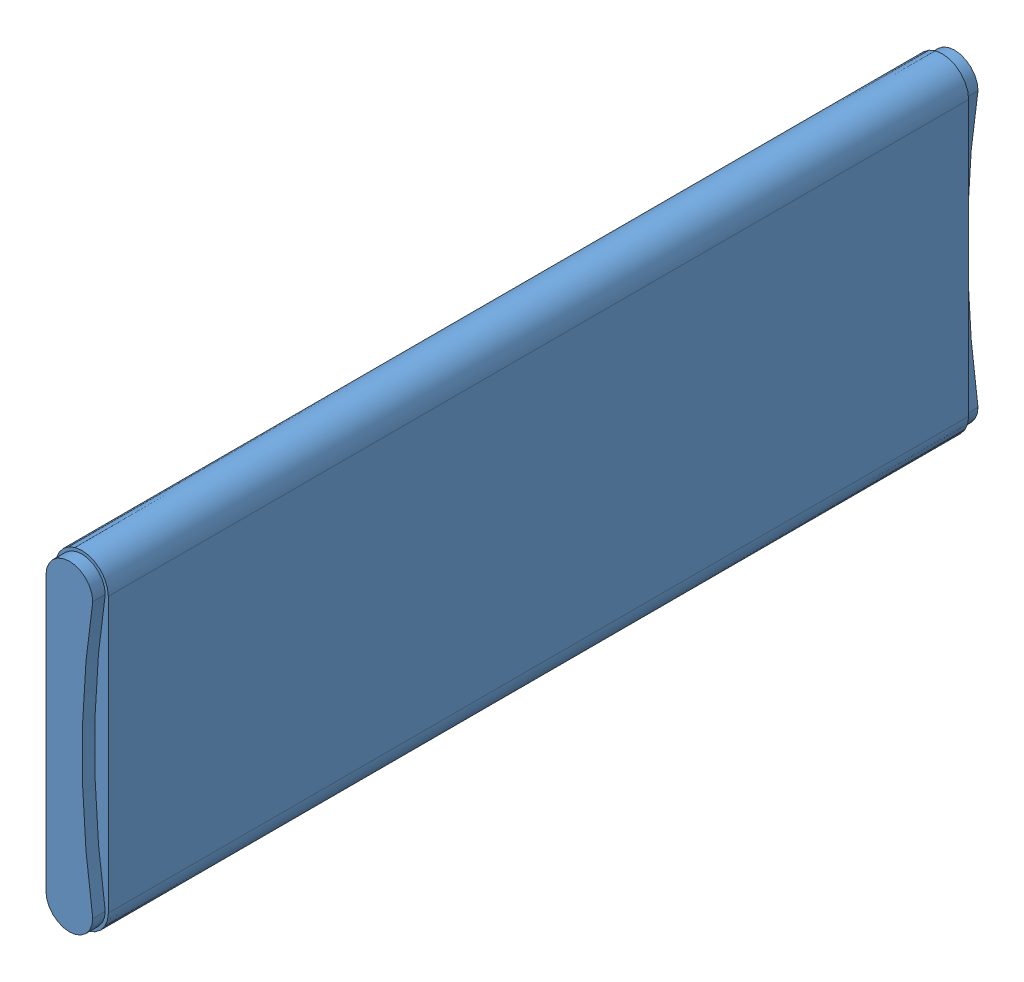
SolidWorks assembly Keyboard, configuration Default. Lengths in mm.
Overall size (33.34 166.69 450.85).
53 component instances, 12 part files, 45 mates.
Components (placement in the parent):
- keyboard-1: keyboard [Default] at (129.1547 266.0626 122.0532) size (33.34 166.69 450.85)
- squre button-1: squre button [Default] at (115.6609 262.8876 162.1375) x (0 1 0) z (0 0 1) size (19.05 6.35 19.05)
- squre button-2: squre button [Default] at (115.6609 262.8876 181.5844) x (0 1 0) z (0 0 1) size (19.05 6.35 19.05)
- squre button-3: squre button [Default] at (115.6609 262.8876 201.0313) x (0 1 0) z (0 0 1) size (19.05 6.35 19.05)
- squre button-4: squre button [Default] at (115.6609 262.8876 220.4782) x (0 1 0) z (0 0 1) size (19.05 6.35 19.05)
- squre button-5: squre button [Default] at (115.6609 262.8876 239.925) x (0 1 0) z (0 0 1) size (19.05 6.35 19.05)
- squre button-6: squre button [Default] at (115.6609 262.8876 259.3719) x (0 1 0) z (0 0 1) size (19.05 6.35 19.05)
- squre button-7: squre button [Default] at (115.6609 262.8876 278.8188) x (0 1 0) z (0 0 1) size (19.05 6.35 19.05)
- squre button-8: squre button [Default] at (115.6609 262.8876 298.2657) x (0 1 0) z (0 0 1) size (19.05 6.35 19.05)
- squre button-9: squre button [Default] at (115.6609 262.8876 317.7125) x (0 1 0) z (0 0 1) size (19.05 6.35 19.05)
- squre button-10: squre button [Default] at (115.6609 262.8876 337.1594) x (0 1 0) z (0 0 1) size (19.05 6.35 19.05)
- squre button-11: squre button [Default] at (115.6609 262.8876 356.6063) x (0 1 0) z (0 0 1) size (19.05 6.35 19.05)
- squre button-12: squre button [Default] at (115.6609 262.8876 376.0532) x (0 1 0) z (0 0 1) size (19.05 6.35 19.05)
- squre button-13: squre button [Default] at (115.6609 243.4407 168.4875) x (0 1 0) z (0 0 1) size (19.05 6.35 19.05)
- squre button-14: squre button [Default] at (115.6609 243.4407 187.9344) x (0 1 0) z (0 0 1) size (19.05 6.35 19.05)
- squre button-15: squre button [Default] at (115.6609 243.4407 207.3813) x (0 1 0) z (0 0 1) size (19.05 6.35 19.05)
- squre button-16: squre button [Default] at (115.6609 243.4407 226.8282) x (0 1 0) z (0 0 1) size (19.05 6.35 19.05)
- squre button-17: squre button [Default] at (115.6609 243.4407 246.275) x (0 1 0) z (0 0 1) size (19.05 6.35 19.05)
- squre button-18: squre button [Default] at (115.6609 243.4407 265.7219) x (0 1 0) z (0 0 1) size (19.05 6.35 19.05)
- squre button-19: squre button [Default] at (115.6609 243.4407 285.1688) x (0 1 0) z (0 0 1) size (19.05 6.35 19.05)
- squre button-20: squre button [Default] at (115.6609 243.4407 304.6157) x (0 1 0) z (0 0 1) size (19.05 6.35 19.05)
- squre button-21: squre button [Default] at (115.6609 243.4407 324.0625) x (0 1 0) z (0 0 1) size (19.05 6.35 19.05)
- squre button-22: squre button [Default] at (115.6609 243.4407 343.5094) x (0 1 0) z (0 0 1) size (19.05 6.35 19.05)
- squre button-23: squre button [Default] at (115.6609 243.4407 362.9563) x (0 1 0) z (0 0 1) size (19.05 6.35 19.05)
- squre button-24: squre button [Default] at (115.6609 243.4407 382.4032) x (0 1 0) z (0 0 1) size (19.05 6.35 19.05)
- squre button-25: squre button [Default] at (115.6609 223.9939 178.0125) x (0 1 0) z (0 0 1) size (19.05 6.35 19.05)
- squre button-26: squre button [Default] at (115.6609 223.9939 197.4594) x (0 1 0) z (0 0 1) size (19.05 6.35 19.05)
- squre button-27: squre button [Default] at (115.6609 223.9939 216.9063) x (0 1 0) z (0 0 1) size (19.05 6.35 19.05)
- squre button-28: squre button [Default] at (115.6609 223.9939 236.3532) x (0 1 0) z (0 0 1) size (19.05 6.35 19.05)
- squre button-29: squre button [Default] at (115.6609 223.9939 255.8) x (0 1 0) z (0 0 1) size (19.05 6.35 19.05)
- squre button-30: squre button [Default] at (115.6609 223.9939 275.2469) x (0 1 0) z (0 0 1) size (19.05 6.35 19.05)
- squre button-31: squre button [Default] at (115.6609 223.9939 294.6938) x (0 1 0) z (0 0 1) size (19.05 6.35 19.05)
- squre button-32: squre button [Default] at (115.6609 223.9939 314.1407) x (0 1 0) z (0 0 1) size (19.05 6.35 19.05)
- squre button-33: squre button [Default] at (115.6609 223.9939 333.5875) x (0 1 0) z (0 0 1) size (19.05 6.35 19.05)
- squre button-34: squre button [Default] at (115.6609 223.9939 353.0344) x (0 1 0) z (0 0 1) size (19.05 6.35 19.05)
- 0-1: 0 [Default] at (115.6609 204.547 521.7063) x (0 0 -1) z (0 1 0) size (38.5 6.35 19.05)
- + nand Enter-1: + nand Enter [Default] at (115.6609 243.4407 541.55) x (0 1 0) z (0 0 1) size (38.5 6.35 19.05)
- + nand Enter-2: + nand Enter [Default] at (115.6609 204.547 541.55) x (0 1 0) z (0 0 1) size (38.5 6.35 19.05)
- Enter-1: Enter [Default] at (115.6609 281.9376 395.5) x (0 0 1) z (0 -1 0) size (22.62 6.35 38.5)
- backspace-1: backspace [Default] at (115.6609 301.3845 385.975) x (0 0 1) z (0 -1 0) size (32.23 6.35 19.05)
- Shift 2-1: Shift 2 [Default] at (115.6609 243.0439 133.1657) x (0 0 1) z (0 -1 0) size (45.64 6.35 19.05)
- Shift 2-2: Shift 2 [Default] at (115.6609 243.0439 372.4813) x (0 0 1) z (0 -1 0) size (45.64 6.35 19.05)
- Shift - Copy-1: Shift - Copy [Default] at (115.6609 281.9376 133.1657) x (0 0 1) z (0 -1 0) size (28.57 6.35 19.05)
- caps ;ock-1: caps ;ock [Default] at (115.6609 262.4907 133.1657) x (0 0 1) z (0 -1 0) size (35.01 6.35 19.05)
- Ctrl-1: Ctrl [Default] at (115.6609 223.597 133.1657) x (0 0 1) z (0 -1 0) size (23.81 6.35 19.05)
- Ctrl-2: Ctrl [Default] at (115.6609 223.597 157.375) x (0 0 1) z (0 -1 0) size (23.81 6.35 19.05)
- Ctrl-3: Ctrl [Default] at (115.6609 223.597 181.5844) x (0 0 1) z (0 -1 0) size (23.81 6.35 19.05)
- Ctrl-11: Ctrl [Default] at (115.6609 204.547 418.1219) x (0 0 -1) z (0 1 0) size (23.81 6.35 19.05)
- Ctrl-12: Ctrl [Default] at (115.6609 204.547 393.9125) x (0 0 -1) z (0 1 0) size (23.81 6.35 19.05)
- Ctrl-13: Ctrl [Default] at (115.6609 204.547 369.7032) x (0 0 -1) z (0 1 0) size (23.81 6.35 19.05)
- Ctrl-14: Ctrl [Default] at (115.6609 204.547 345.4938) x (0 0 -1) z (0 1 0) size (23.81 6.35 19.05)
- Space-1: Space [Default] at (115.6609 223.597 205.7938) x (0 0 1) z (0 -1 0) size (115.49 6.35 19.05)
- Part2^Keyboard-1: Part2^Keyboard [Default] at origin (virtual)
Mates (geometry in assembly coordinates):
- Coincident1: coincident anti-aligned: plane of keyboard-1 through (115.6609 196.2126 572.9032) normal (-1 0 0); plane of squre button-1 through (115.6609 262.8876 162.1375) normal (1 0 0)
- Distance1: distance = 0.3969 mm: line of squre button-1 through (115.6609 281.9376 162.1375) axis (0 0 1); line of keyboard-1 through (115.6609 282.3345 152.6125) axis (0 0 1)
- Distance3: distance = 9.525 mm: line of squre button-1 through (115.6609 262.8876 162.1375) axis (0 1 0); line of keyboard-1 through (115.6609 282.3345 171.6625) axis (0 1 0)
- Coincident5: coincident anti-aligned: plane of keyboard-1 through (115.6609 196.2126 572.9032) normal (-1 0 0); plane of squre button-13 through (115.6609 243.4407 168.4875) normal (1 0 0)
- Distance4: distance = 0.3969 mm: line of squre button-13 through (115.6609 262.4907 168.4875) axis (0 0 1); line of squre button-1 through (115.6609 262.8876 162.1375) axis (0 0 1)
- Distance5: distance = 12.7 mm: line of squre button-13 through (115.6609 243.4407 168.4875) axis (0 1 0); line of squre button-1 through (115.6609 262.8876 181.1875) axis (0 1 0)
- Coincident8: coincident anti-aligned: plane of keyboard-1 through (115.6609 196.2126 572.9032) normal (-1 0 0); plane of squre button-25 through (115.6609 223.9939 178.0125) normal (1 0 0)
- Distance6: distance = 0.3969 mm: line of squre button-25 through (115.6609 243.0439 178.0125) axis (0 0 1); line of squre button-13 through (115.6609 243.4407 168.4875) axis (0 0 1)
- Distance7: distance = 9.525 mm: line of squre button-25 through (115.6609 223.9939 178.0125) axis (0 1 0); line of squre button-13 through (115.6609 243.4407 187.5375) axis (0 1 0)
- Coincident11: coincident anti-aligned: plane of keyboard-1 through (115.6609 196.2126 572.9032) normal (-1 0 0); plane of 0-1 through (115.6609 204.547 521.7063) normal (1 0 0)
- Distance12: distance = 0.3969 mm: line of 0-1 through (115.6609 204.547 521.7063) axis (0 0 -1); line of keyboard-1 through (115.6609 204.1501 483.2094) axis (0 0 1)
- Coincident16: coincident anti-aligned: line of keyboard-1 through (115.6609 243.0439 483.2094) axis (0 -1 0); line of 0-1 through (115.6609 204.547 483.2094) axis (0 1 0)
- Coincident17: coincident anti-aligned: plane of keyboard-1 through (115.6609 196.2126 572.9032) normal (-1 0 0); plane of + nand Enter-1 through (115.6609 243.4407 541.55) normal (1 0 0)
- Distance13: distance = 0.3969 mm: line of + nand Enter-1 through (115.6609 281.9376 560.6) axis (0 0 -1); line of keyboard-1 through (115.6609 282.3345 541.55) axis (0 0 1)
- Coincident19: coincident aligned: line of keyboard-1 through (115.6609 301.3845 541.55) axis (0 -1 0); line of + nand Enter-1 through (115.6609 281.9376 541.55) axis (0 -1 0)
- Coincident20: coincident anti-aligned: plane of keyboard-1 through (115.6609 196.2126 572.9032) normal (-1 0 0); plane of + nand Enter-2 through (115.6609 204.547 541.55) normal (1 0 0)
- Distance14: distance = 0.3969 mm: line of + nand Enter-2 through (115.6609 243.0439 560.6) axis (0 0 -1); line of + nand Enter-1 through (115.6609 243.4407 541.55) axis (0 0 1)
- Coincident22: coincident aligned: line of + nand Enter-1 through (115.6609 281.9376 541.55) axis (0 -1 0); line of + nand Enter-2 through (115.6609 243.0439 541.55) axis (0 -1 0)
- Coincident24: coincident anti-aligned: plane of keyboard-1 through (115.6609 196.2126 572.9032) normal (-1 0 0); plane of Enter-1 through (115.6609 281.9376 395.5) normal (1 0 0)
- Coincident37: coincident aligned: line of squre button-12 through (115.6609 281.9376 376.0532) axis (0 0 1); line of Enter-1 through (115.6609 281.9376 395.5) axis (0 0 1)
- Distance24: distance = 0.3969 mm: line of Enter-1 through (115.6609 262.8876 395.5) axis (0 1 0); line of squre button-12 through (115.6609 262.8876 395.1032) axis (0 1 0)
- Coincident39: coincident anti-aligned: plane of keyboard-1 through (115.6609 196.2126 572.9032) normal (-1 0 0); plane of backspace-1 through (115.6609 301.3845 385.975) normal (1 0 0)
- Distance27: distance = 0.3969 mm: line of backspace-1 through (115.6609 301.3845 385.975) axis (0 -1 0); line of keyboard-1 through (115.6609 282.3345 385.5782) axis (0 1 0)
- Coincident44: coincident aligned: line of keyboard-1 through (115.6609 301.3845 385.5782) axis (0 0 -1); line of backspace-1 through (115.6609 301.3845 418.2013) axis (0 0 -1)
- Coincident45: coincident anti-aligned: plane of keyboard-1 through (115.6609 196.2126 572.9032) normal (-1 0 0); plane of Shift 2-1 through (115.6609 243.0439 133.1657) normal (1 0 0)
- Coincident47: coincident aligned: line of squre button-34 through (115.6609 243.0439 353.0344) axis (0 0 1); line of Shift 2-1 through (115.6609 243.0439 133.1657) axis (0 0 1)
- Distance32: distance = 0.3969 mm: line of Shift 2-1 through (115.6609 243.0439 133.1657) axis (0 -1 0); line of keyboard-1 through (115.6609 301.3845 132.7688) axis (0 -1 0)
- Coincident55: coincident anti-aligned: plane of keyboard-1 through (115.6609 196.2126 572.9032) normal (-1 0 0); plane of Shift 2-2 through (115.6609 243.0439 372.4813) normal (1 0 0)
- Coincident57: coincident aligned: line of squre button-34 through (115.6609 243.0439 353.0344) axis (0 0 1); line of Shift 2-2 through (115.6609 243.0439 372.4813) axis (0 0 1)
- Distance33: distance = 0.3969 mm: line of Shift 2-2 through (115.6609 243.0439 372.4813) axis (0 -1 0); line of squre button-34 through (115.6609 223.9939 372.0844) axis (0 1 0)
- Coincident59: coincident anti-aligned: plane of keyboard-1 through (115.6609 196.2126 572.9032) normal (-1 0 0); plane of Shift - Copy-1 through (115.6609 281.9376 133.1657) normal (1 0 0)
- Coincident62: coincident aligned: line of squre button-1 through (115.6609 281.9376 162.1375) axis (0 0 1); line of Shift - Copy-1 through (115.6609 281.9376 133.1657) axis (0 0 1)
- Distance34: distance = 0.3969 mm: line of Shift - Copy-1 through (115.6609 281.9376 133.1657) axis (0 -1 0); line of keyboard-1 through (115.6609 301.3845 132.7688) axis (0 -1 0)
- Coincident63: coincident anti-aligned: plane of keyboard-1 through (115.6609 196.2126 572.9032) normal (-1 0 0); plane of caps ;ock-1 through (115.6609 262.4907 133.1657) normal (1 0 0)
- Coincident64: coincident aligned: line of squre button-13 through (115.6609 262.4907 168.4875) axis (0 0 1); line of caps ;ock-1 through (115.6609 262.4907 133.1657) axis (0 0 1)
- Coincident65: coincident aligned: line of Shift - Copy-1 through (115.6609 281.9376 133.1657) axis (0 -1 0); line of caps ;ock-1 through (115.6609 262.4907 133.1657) axis (0 -1 0)
- Coincident66: coincident anti-aligned: plane of keyboard-1 through (115.6609 196.2126 572.9032) normal (-1 0 0); plane of Ctrl-1 through (115.6609 223.597 133.1657) normal (1 0 0)
- Coincident69: coincident aligned: line of Ctrl-1 through (115.6609 223.597 133.1657) axis (0 -1 0); line of Shift 2-1 through (115.6609 243.0439 133.1657) axis (0 -1 0)
- Distance37: distance = 0.3969 mm: line of Ctrl-1 through (115.6609 223.597 133.1657) axis (0 0 1); line of Shift 2-1 through (115.6609 223.9939 133.1657) axis (0 0 1)
- Coincident71: coincident anti-aligned: plane of keyboard-1 through (115.6609 196.2126 572.9032) normal (-1 0 0); plane of Ctrl-11 through (115.6609 204.547 418.1219) normal (1 0 0)
- Coincident73: coincident anti-aligned: line of Ctrl-3 through (115.6609 223.597 181.5844) axis (0 0 1); line of Ctrl-11 through (115.6609 223.597 418.1219) axis (0 0 -1)
- Coincident74: coincident anti-aligned: line of Shift 2-2 through (115.6609 243.0439 418.1219) axis (0 -1 0); line of Ctrl-11 through (115.6609 204.547 418.1219) axis (0 1 0)
- Coincident75: coincident anti-aligned: plane of keyboard-1 through (115.6609 196.2126 572.9032) normal (-1 0 0); plane of Space-1 through (115.6609 223.597 205.7938) normal (1 0 0)
- Coincident76: coincident aligned: line of Ctrl-3 through (115.6609 223.597 181.5844) axis (0 0 1); line of Space-1 through (115.6609 223.597 205.7938) axis (0 0 1)
- Distance38: distance = 0.3969 mm: line of Space-1 through (115.6609 223.597 205.7938) axis (0 -1 0); line of Ctrl-3 through (115.6609 223.597 205.3969) axis (0 -1 0)
